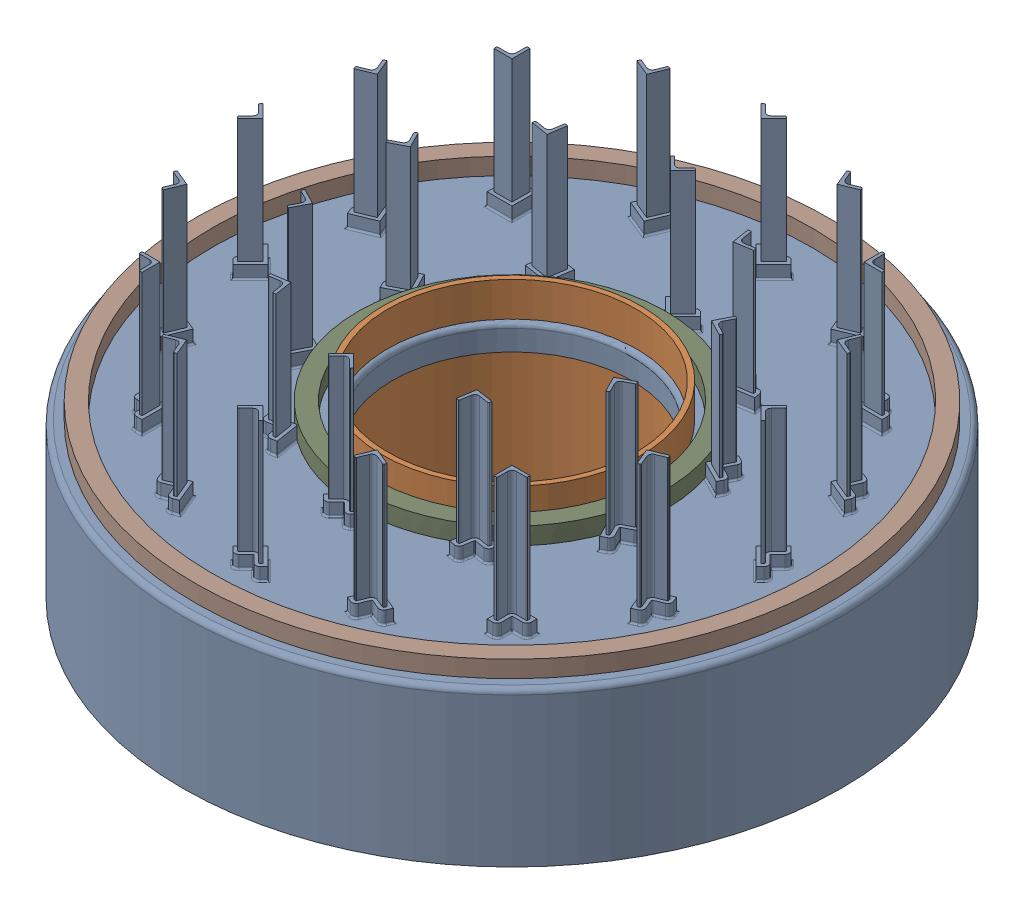
SolidWorks assembly Assem2, configuration Default. Lengths in mm.
Overall size (1303.07 431.8 1303.07).
17 component instances, 9 part files, 19 mates.
Components (placement in the parent):
- flat_shell_design-1: flat_shell_design [Default] at (-60.9942 -27.4812 -51.2064) size (977.9 431.8 977.9)
- cyinder-1: cyinder [Default] at (-60.9942 -27.4812 -51.2064) x (0.996317 0 -0.085744) z (0.085744 0 0.996317) size (383.54 279.4 383.54)
- quick frame-1: quick frame [Default] at (108.1647 201.1188 -163.7919) x (0.832475 0 -0.554063) z (0.554063 0 0.832475) size (939.8 254 939.8)
- basic cam mockup-1: basic cam mockup [Default] at (-154.1674 169.5188 -263.3712) x (-0.832475 0 0.554063) z (0.554063 0 0.832475) size (88 94 76)
- basic cam mockup-2: basic cam mockup [Default] at (151.1707 169.5188 -144.3796) x (-0.554063 0 -0.832475) z (-0.832475 0 0.554063) size (88 94 76)
- basic cam mockup-3: basic cam mockup [Default] at (-413.5074 131.9381 -79.0444) x (0.080235 0 0.996776) z (-0.640715 0.766044 0.051574) size (88 94 76)
- basic cam mockup-4: basic cam mockup [Default] at (91.154 131.9381 267.9981) x (0.823116 0 -0.567874) z (0.365022 0.766044 0.529089) size (88 94 76)
- basic cam mockup-5: basic cam mockup [Default] at (139.3709 131.9381 -342.5728) x (-0.903351 0 -0.428902) z (0.275693 0.766044 -0.580663) size (88 94 76)
- basic cam mockup-6: basic cam mockup [Default] at (161.7387 54.4773 121.0759) x (0.46704 0 -0.884236) z (0.568376 -0.766044 0.300208) size (88 94 76)
- basic cam mockup-7: basic cam mockup [Default] at (-23.1598 54.4773 -330.2398) x (-0.999291 0 0.037649) z (-0.024201 -0.766044 -0.642332) size (88 94 76)
- basic cam mockup-8: basic cam mockup [Default] at (-321.5614 54.4773 55.5449) x (0.532251 0 0.846587) z (-0.544175 -0.766044 0.342124) size (88 94 76)
- Asus hyper m.2 x16 gen 4-1: Asus hyper m.2 x16 gen 4 [Default] at (-220.1149 -27.4812 -433.9548) size (279 86 56.75)
- ECEboard_large-1: ECEboard_large [Default] at (351.5022 -20.9748 -127.7433) x (-0.414693 0 -0.909961) z (0 -1 0) size (231.28 7.5 173.9)
- ECEboard_small-1: ECEboard_small [Default] at (232.5503 -11.6953 -364.2127) x (-0.93358 0 -0.358368) z (0 -1 0) size (174 7.5 130)
- jetson holder-1: jetson holder [Default] at (-328.2955 133.698 -388.1902) x (0.830573 0 -0.55691) z (0 1 0) size (99.2 7.5 135)
- jetson holder-2: jetson holder [Default] at (-363.1887 14.7421 -361.715) x (-0.636078 0 0.771625) z (0 -1 0) size (99.2 7.5 135)
- startech-1: startech [Default] at (-13.005 -3.2289 373.3918) x (-1 0 0) z (0 -1 0) size (165.48 7.56 82.4)
Mates (geometry in assembly coordinates):
- Concentric1: concentric aligned: cylinder of flat_shell_design-1 through (-60.9942 -27.4812 -51.2064) axis (0 -1 0) radius 184.15; cylinder of cyinder-1 through (-60.9942 251.9188 -51.2064) axis (0 -1 0) radius 184.15
- Coincident1: coincident aligned: plane of flat_shell_design-1 through (427.9558 -27.4812 -51.2064) normal (0 -1 0); plane of cyinder-1 through (-60.9942 -27.4812 -51.2064) normal (0 -1 0)
- Concentric2: concentric anti-aligned: cylinder of cyinder-1 through (-60.9942 251.9188 -51.2064) axis (0 -1 0) radius 191.77; cylinder of quick frame-1 through (-60.9942 236.7411 -51.2064) axis (0 1 0) radius 203.2
- Coincident2: coincident aligned: plane of cyinder-1 through (-60.9942 -27.4812 -51.2064) normal (0 -1 0); plane of quick frame-1 through (108.1647 -27.4812 -163.7919) normal (0 -1 0)
- Coincident4: coincident anti-aligned: plane of quick frame-1 through (-198.0476 -27.4812 -234.1663) normal (-0.554063 0 -0.832475); plane of basic cam mockup-1 through (-154.1674 75.5188 -263.3712) normal (0.554063 0 0.832475)
- Parallel1: parallel aligned: plane of cyinder-1 through (-60.9942 -27.4812 -51.2064) normal (0 -1 0); plane of basic cam mockup-1 through (-154.1674 75.5188 -263.3712) normal (0 -1 0)
- Distance1: distance = 150 mm aligned: point of basic cam mockup-1; plane of quick frame-1 through (108.1647 -27.4812 -163.7919) normal (0 -1 0)
- Angle1: planar angle = 2.443461 rad: plane of basic cam mockup-3 through (-293.0371 134.1408 -88.7416) normal (0.640715 -0.766044 -0.051574); plane of quick frame-1 through (108.1647 201.1188 -163.7919) normal (0 -1 0)
- Distance2: distance = 25 mm: plane of quick frame-1 through (108.1647 48.7188 -163.7919) normal (0 1 0); line of basic cam mockup-3 through (-357.7524 73.7188 4.7522) axis (-0.080235 0 -0.996776)
- Coincident13: coincident: cylinder of assembly; point of assembly; cylinder of quick frame-1 through (-60.9942 236.7411 -51.2064) axis (0 1 0) radius 228.6; moEndPointRef_w of basic cam mockup-3
- Angle2: planar angle = 2.443461 rad aligned: plane of basic cam mockup-6 through (182.2144 173.1188 131.8908) normal (-0.568376 0.766044 -0.300208); plane of quick frame-1 through (108.1647 201.1188 -163.7919) normal (0 -1 0)
- Distance3: distance = 28 mm: line of basic cam mockup-6 through (223.3139 173.1188 54.078) axis (-0.46704 0 0.884236); plane of quick frame-1 through (108.1647 201.1188 -163.7919) normal (0 -1 0)
- Coincident16: coincident: cylinder of quick frame-1 through (-60.9942 236.7411 -51.2064) axis (0 1 0) radius 228.6; unknown of basic cam mockup-6
- Coincident18: coincident aligned: plane of quick frame-1 through (108.1647 -27.4812 -163.7919) normal (0 -1 0); plane of Asus hyper m.2 x16 gen 4-1 through (-220.1149 -27.4812 -433.9548) normal (0 -1 0)
- Parallel5: parallel aligned: plane of Asus hyper m.2 x16 gen 4-1 through (-220.1149 -27.4812 -433.9548) normal (0 -1 0); plane of ECEboard_large-1 through (359.7784 -24.4748 -127.6686) normal (0 -1 0)
- Parallel6: parallel aligned: plane of Asus hyper m.2 x16 gen 4-1 through (-220.1149 -27.4812 -433.9548) normal (0 -1 0); plane of ECEboard_small-1 through (235.238 -11.6953 -371.2146) normal (0 -1 0)
- Parallel7: parallel aligned: plane of Asus hyper m.2 x16 gen 4-1 through (-220.1149 -27.4812 -433.9548) normal (0 -1 0); plane of startech-1 through (-169.98 -2.0789 365.8918) normal (0 -1 0)
- Parallel9: parallel aligned: plane of Asus hyper m.2 x16 gen 4-1 through (-220.1149 -27.4812 -433.9548) normal (0 -1 0); plane of jetson holder-1 through (-228.8169 -17.2918 -404.1488) normal (0 -1 0)
- Parallel8: parallel anti-aligned: plane of Asus hyper m.2 x16 gen 4-1 through (-220.1149 -27.4812 -433.9548) normal (0 -1 0); plane of jetson holder-2 through (-407.6373 129.1577 -416.9034) normal (0 1 0)
